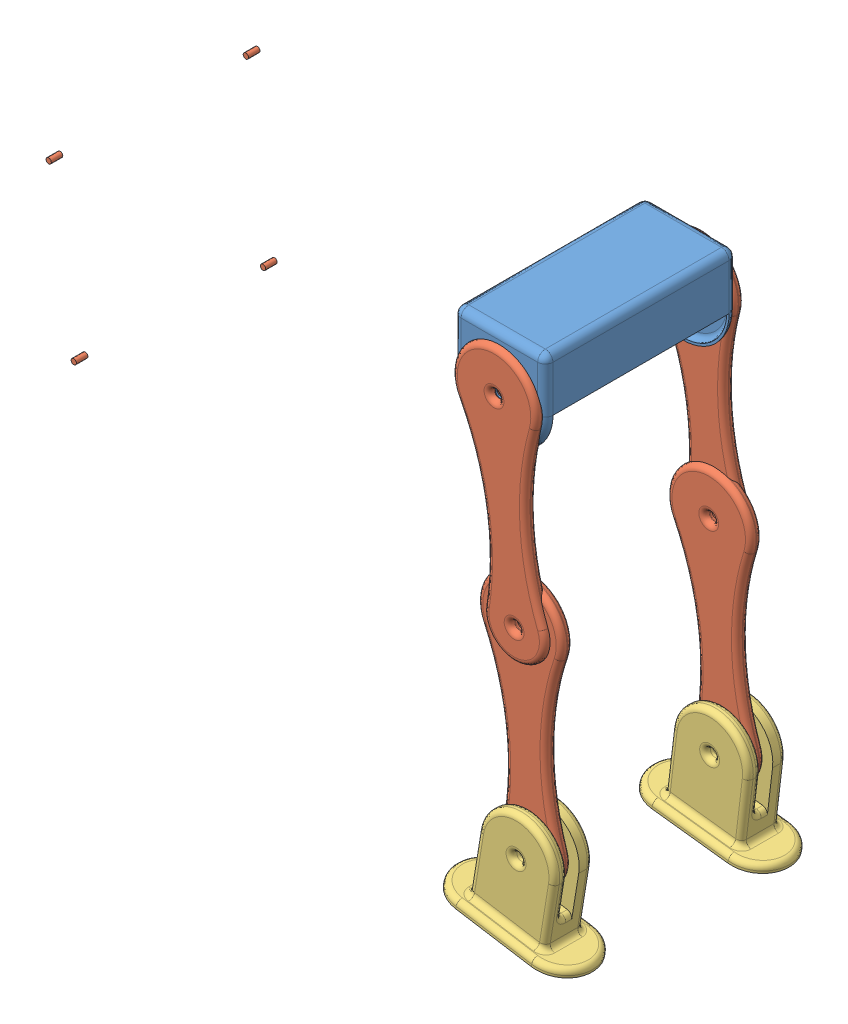
SolidWorks assembly robot1, configuration Default. Lengths in mm.
Overall size (731.25 671.54 323).
7 component instances, 3 part files, 13 mates.
Components (placement in the parent):
- base-1: base [Default] at origin size (120 640 250)
- right leg ^robot1-7: right leg ^robot1 [Default] at (27.955 321.3823 110) x (0.998647 0.052009 0) z (0 0 1) size (639.35 345 15) (virtual)
- foot^robot1-4: foot^robot1 [Default] at (26.5331 -17.1159 117.5) x (0.987073 -0.160269 0) z (0 0 1) size (180 140 80) (virtual)
- right leg ^robot1-8: right leg ^robot1 [Default] at (1.7012 570 117) x (0.994471 0.105015 0) z (0 0 1) size (639.35 345 15) (virtual)
- right leg ^robot1-9: right leg ^robot1 [Default] at (1.7012 570 -140) x (0.992583 0.121567 0) z (0 0 1) size (639.35 345 15) (virtual)
- right leg ^robot1-10: right leg ^robot1 [Default] at (32.0929 321.8542 -133) x (0.997209 0.074658 0) z (0 0 1) size (639.35 345 15) (virtual)
- foot^robot1-5: foot^robot1 [Default] at (40.0724 -16.8116 -125.5) x (0.992927 -0.118723 0) z (0 0 1) size (180 140 80) (virtual)
Mates (geometry in assembly coordinates):
- Concentric12: concentric: circle of assembly; circle of assembly; circle of base-1; circle of right leg ^robot1-8
- Coincident14: coincident: plane of assembly; circle of assembly; plane of base-1 through (1.7012 570 125) normal (0 0 1); circle of right leg ^robot1-8
- Concentric13: concentric: circle of assembly; circle of assembly; circle of right leg ^robot1-7; circle of right leg ^robot1-8
- Coincident15: coincident: circle of assembly; plane of assembly; circle of right leg ^robot1-7; plane of right leg ^robot1-8 through (209.9298 391.455 117) normal (0 0 -1)
- Concentric14: concentric: circle of assembly; circle of assembly; circle of right leg ^robot1-7; circle of foot^robot1-4
- Coincident16: coincident: plane of assembly; circle of assembly; plane of right leg ^robot1-7 through (226.3993 132.022 125) normal (0 0 1); circle of foot^robot1-4
- Concentric15: concentric: circle of base-1; circle of ?
- Coincident20: coincident: plane of base-1 through (1.7012 570 -125) normal (0 0 -1); plane of ? through (209.5978 391.0685 -125) normal (0 0 1)
- Concentric16: concentric: circle of ?; circle of ?
- Coincident21: coincident: plane of ? through (209.5978 391.0685 -125) normal (0 0 1); circle of ?
- Concentric17: concentric: circle of ?; circle of ?
- Coincident23: coincident: plane of ? through (215.0507 121.1848 -133) normal (0 0 -1); circle of ?
- Tangent4: tangent: plane of assembly; circle of assembly; plane of right leg ^robot1-7 through (226.3993 132.022 110) normal (0 0 -1); circle of foot^robot1-4
